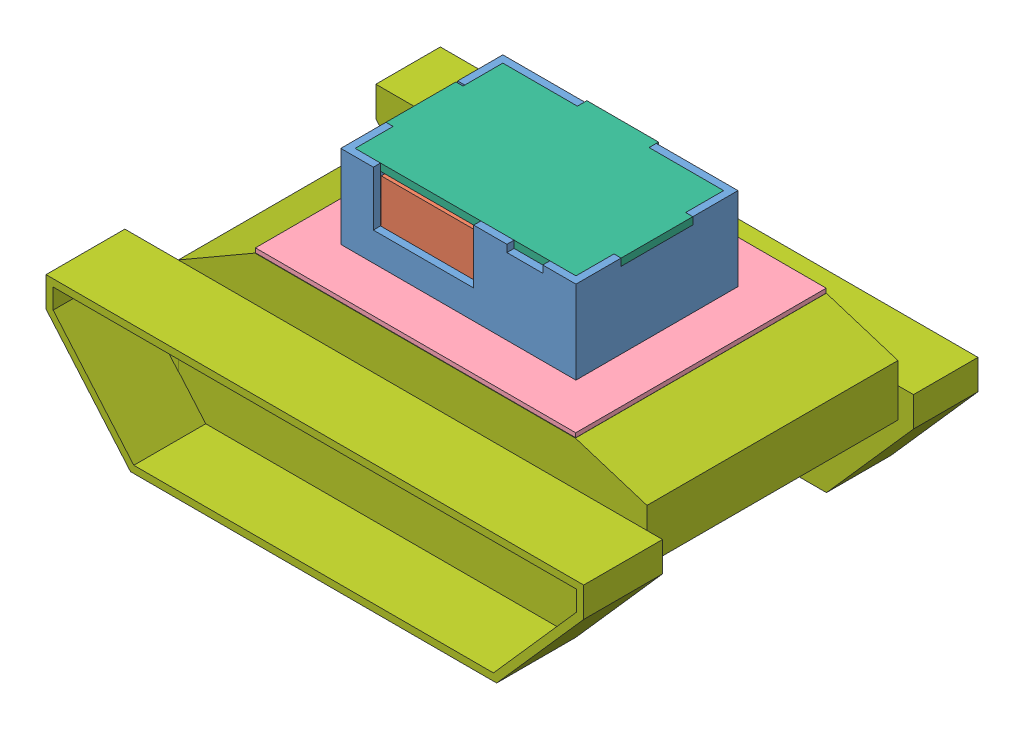
SolidWorks assembly Assemblage chassis 1, configuration Default. Lengths in mm.
Overall size (374.95 183.41 275).
10 component instances, 7 part files, 25 mates.
Components (placement in the parent):
- boite-1: boite [Default] at (-87.4002 206.352 80.3922) size (164 58 113)
- carte-1: carte [Default] at (-86.4002 223.352 81.6422) size (154 33 101.5)
- fixation-1: fixation [Default] at (-87.4002 196.352 80.3922) size (70 10 70)
- plaque-1: plaque [Default] at (-87.4002 201.352 80.3922) x (0 0 -1) z (1 0 0) size (174.68 3 223.37)
- entretoise-1: entretoise [Default] at (-17.4002 211.352 37.8922) x (0.957177 0 0.289503) z (-0.289503 0 0.957177) size (8 12 8)
- entretoise-2: entretoise [Default] at (-157.4002 211.352 37.8922) size (8 12 8)
- entretoise-4: entretoise [Default] at (-157.4002 211.352 125.8922) x (0.969192 0 0.246308) z (-0.246308 0 0.969192) size (8 12 8)
- entretoise-5: entretoise [Default] at (-17.4002 211.352 125.8922) x (0.714568 0 -0.699566) z (0.699566 0 0.714568) size (8 12 8)
- plexi haut-1: plexi haut [Default] at (-87.4002 259.352 81.3922) size (164 5 109.63)
- chassis-1: chassis [Default] at (-103.2035 154.2036 -6.9478) size (374.95 120.41 275)
Mates (geometry in assembly coordinates):
- Coaxiale1: concentric aligned: cylinder of fixation-1 through (-87.4002 206.352 80.3922) axis (0 -1 0) radius 26; cylinder of plaque-1 through (-87.4002 204.352 80.3922) axis (0 -1 0) radius 26
- Coïncidente1: coincident anti-aligned: plane of fixation-1 through (-87.4002 201.352 80.3922) normal (0 1 0); plane of plaque-1 through (-87.4002 201.352 80.3922) normal (0 -1 0)
- Coaxiale2: concentric anti-aligned: cylinder of boite-1 through (-87.4002 206.352 80.3922) axis (0 1 0) radius 16; cylinder of fixation-1 through (-87.4002 206.352 80.3922) axis (0 -1 0) radius 16
- Coïncidente2: coincident aligned: circle of boite-1; cylinder of fixation-1 through (-87.4002 171.352 59.3922) axis (0 1 0) radius 1.5
- Parallèle1: parallel aligned: cylinder of boite-1 through (-157.4002 206.352 37.8922) axis (0 1 0) radius 1.5; cylinder of carte-1 through (-157.4002 223.352 37.8922) axis (0 1 0) radius 1.5
- Coïncidente3: coincident anti-aligned: plane of carte-1 through (-86.4002 223.352 81.6422) normal (0 -1 0); plane of entretoise-2 through (-157.4002 223.352 37.8922) normal (0 1 0)
- Coaxiale5: concentric anti-aligned: cylinder of carte-1 through (-157.4002 223.352 37.8922) axis (0 1 0) radius 1.5; cylinder of entretoise-2 through (-157.4002 223.352 37.8922) axis (0 -1 0) radius 1.5
- Coaxiale6: concentric anti-aligned: cylinder of carte-1 through (-17.4002 223.352 37.8922) axis (0 1 0) radius 1.5; cylinder of entretoise-1 through (-17.4002 223.352 37.8922) axis (0 -1 0) radius 1.5
- Coïncidente4: coincident anti-aligned: plane of carte-1 through (-86.4002 223.352 81.6422) normal (0 -1 0); plane of entretoise-1 through (-17.4002 223.352 37.8922) normal (0 1 0)
- Coaxiale7: concentric anti-aligned: cylinder of carte-1 through (-157.4002 223.352 125.8922) axis (0 1 0) radius 1.5; cylinder of entretoise-4 through (-157.4002 223.352 125.8922) axis (0 -1 0) radius 1.5
- Coïncidente5: coincident anti-aligned: plane of carte-1 through (-86.4002 223.352 81.6422) normal (0 -1 0); plane of entretoise-4 through (-157.4002 223.352 125.8922) normal (0 1 0)
- Coaxiale8: concentric anti-aligned: cylinder of carte-1 through (-17.4002 223.352 125.8922) axis (0 1 0) radius 1.5; cylinder of entretoise-5 through (-17.4002 223.352 125.8922) axis (0 -1 0) radius 1.5
- Coïncidente6: coincident anti-aligned: plane of carte-1 through (-86.4002 223.352 81.6422) normal (0 -1 0); plane of entretoise-5 through (-17.4002 223.352 125.8922) normal (0 1 0)
- Coaxiale11: concentric anti-aligned: cylinder of boite-1 through (-157.4002 206.352 37.8922) axis (0 1 0) radius 1.5; cylinder of entretoise-2 through (-157.4002 223.352 37.8922) axis (0 -1 0) radius 1.5
- Coaxiale12: concentric anti-aligned: cylinder of boite-1 through (-17.4002 206.352 37.8922) axis (0 1 0) radius 1.5; cylinder of entretoise-1 through (-17.4002 223.352 37.8922) axis (0 -1 0) radius 1.5
- Coaxiale13: concentric anti-aligned: cylinder of boite-1 through (-17.4002 206.352 125.8922) axis (0 1 0) radius 1.5; cylinder of entretoise-5 through (-17.4002 223.352 125.8922) axis (0 -1 0) radius 1.5
- Coïncidente9: coincident anti-aligned: plane of boite-1 through (-87.4002 211.352 80.3922) normal (0 1 0); plane of entretoise-1 through (-17.4002 211.352 37.8922) normal (0 -1 0)
- Coïncidente10: coincident anti-aligned: plane of boite-1 through (-87.4002 259.352 80.3922) normal (0 1 0); plane of plexi haut-1 through (-87.4002 259.352 81.3922) normal (0 -1 0)
- Coïncidente11: coincident aligned: plane of boite-1 through (-5.4002 206.352 24.8922) normal (1 0 0); plane of plexi haut-1 through (-5.4002 264.352 106.3922) normal (1 0 0)
- Coïncidente12: coincident anti-aligned: plane of boite-1 through (-10.4002 259.352 106.3922) normal (0 0 -1); plane of plexi haut-1 through (-10.4002 264.352 106.3922) normal (0 0 1)
- Coïncidente13: coincident anti-aligned: plane of plaque-1 through (-87.4002 201.352 80.3922) normal (0 -1 0); plane of chassis-1 through (-199.0852 201.352 168.0522) normal (0 1 0)
- Coïncidente14: coincident: plane of plaque-1 through (24.2848 204.352 -6.9478) normal (0 0 -1); line of chassis-1 through (24.3746 201.352 -6.9478) axis (-1 0 0)
- Coïncidente15: coincident anti-aligned: line of plaque-1 through (-199.0852 201.352 -6.9478) axis (0 0 1); line of chassis-1 through (-199.0852 201.352 168.0522) axis (0 0 -1)
- Coïncidente16: coincident anti-aligned: plane of boite-1 through (-87.4002 206.352 80.3922) normal (0 -1 0); plane of fixation-1 through (-87.4002 206.352 80.3922) normal (0 1 0)
- Parallèle2: parallel anti-aligned: plane of boite-1 through (-5.4002 206.352 24.8922) normal (1 0 0); plane of chassis-1 through (-252.5181 -269.5146 168.0522) normal (-1 0 0)
